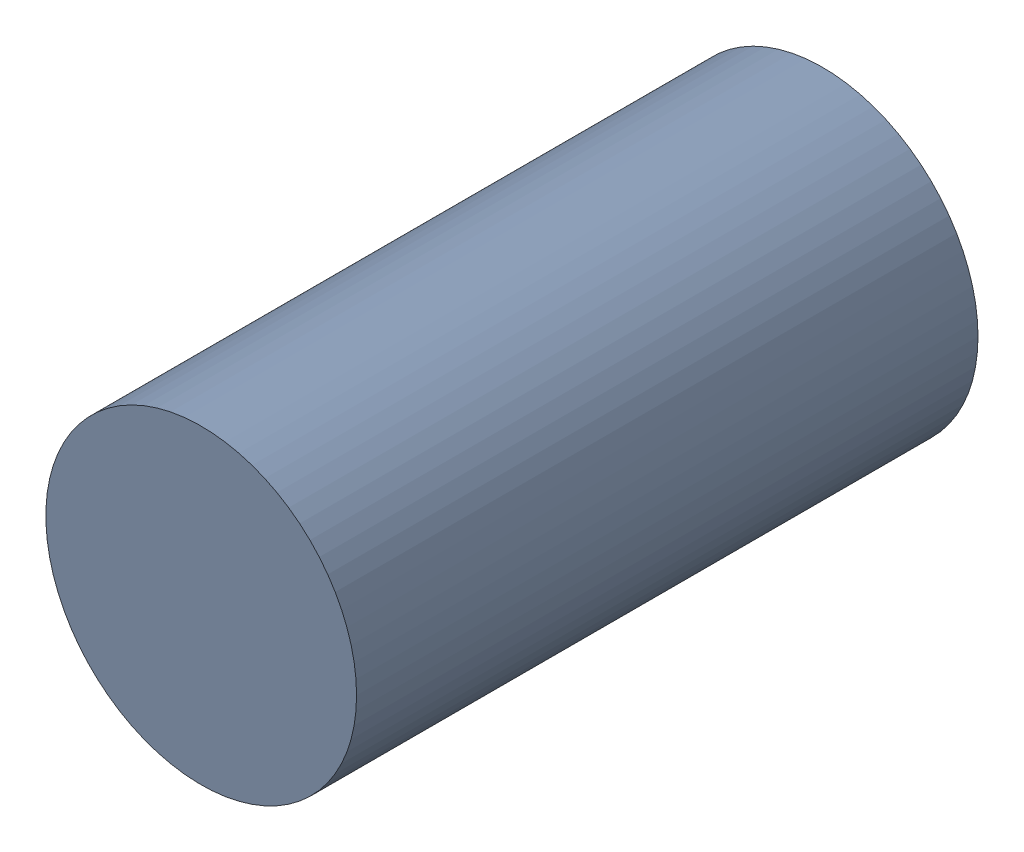
SolidWorks assembly MH11, configuration Default. Lengths in mm.
Overall size (1 1 2).
2 component instances, 1 part files, 0 mates.
Components (placement in the parent):
- 9228463120-1: 9228463120 [Default] at (112.979 80.6107 -1.5) size (1 1 2)
  - Cylinder-1: Cylinder [Default] at origin size (1 1 2)
